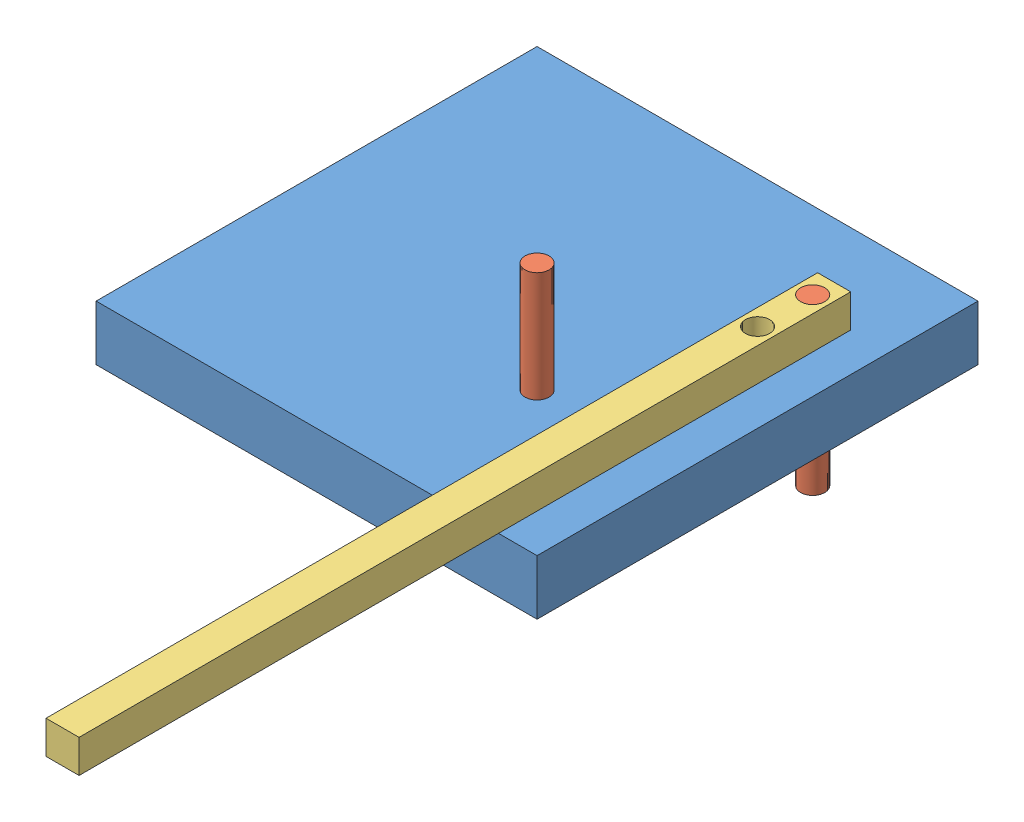
SolidWorks assembly HookAssembly, configuration Default. Lengths in mm.
Overall size (40 22 78.05).
5 component instances, 4 part files, 3 mates.
Components (placement in the parent):
- Chassis Base-1: Chassis Base [Default] at origin size (40 5 40)
- 15mm_Pin-1: 15mm_Pin [Default] at (27 0 -13) size (2.2 15 2.2)
- Part4^HookAssembly-1: Part4^HookAssembly [Default] at origin (virtual)
- HOOK-5: HOOK [Default] at (33.5 5 38.0475) size (3 3 70)
- 15mm_Pin-5: 15mm_Pin [Default] at (35 -7 -30) size (2.2 15 2.2)
Mates (geometry in assembly coordinates):
- Coincident37: coincident anti-aligned: plane of Chassis Base-1 through (0 5 0) normal (0 1 0); plane of HOOK-5 through (33.5 5 38.0475) normal (0 -1 0)
- Coincident38: coincident aligned: circle of Chassis Base-1; circle of HOOK-5
- Coincident46: coincident aligned: plane of HOOK-5 through (33.5 8 38.0475) normal (0 1 0); circle of 15mm_Pin-5
